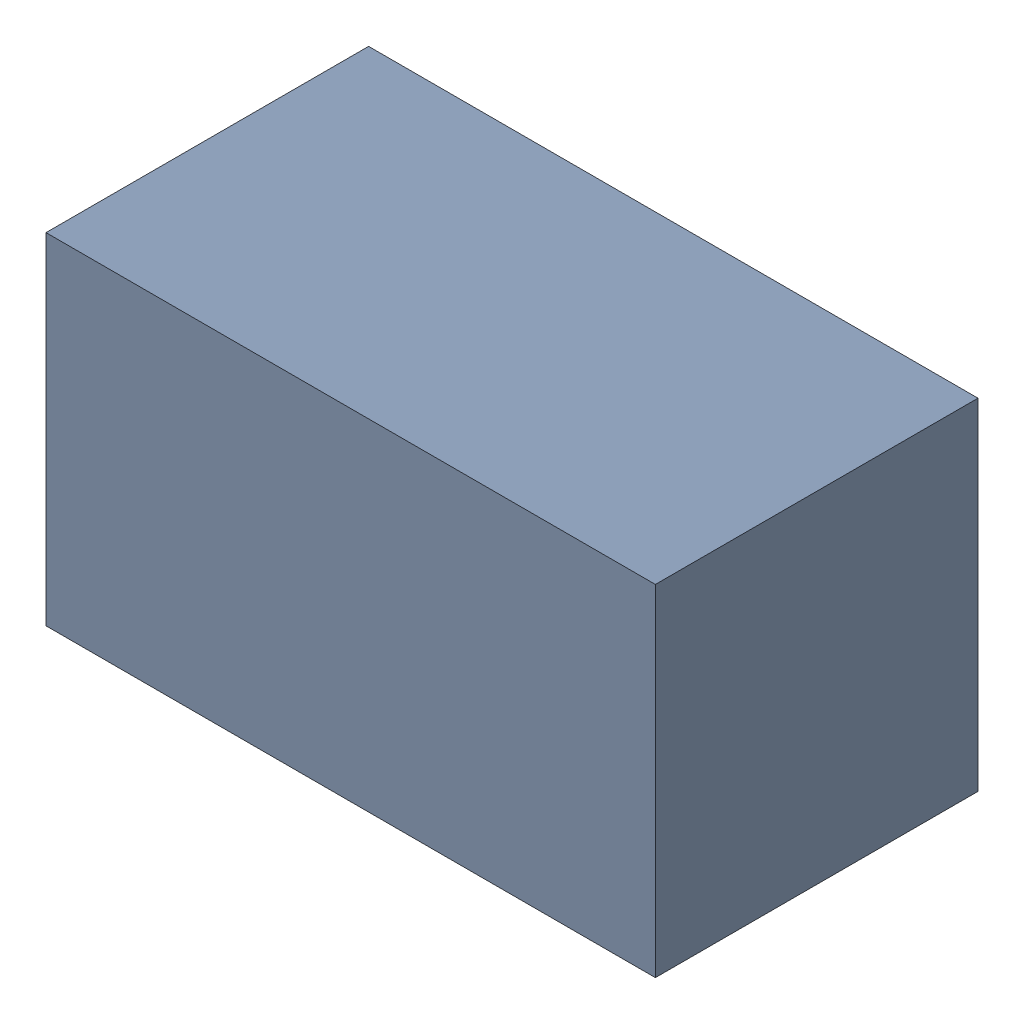
SolidWorks assembly R25, configuration Standard. Lengths in mm.
Overall size (1.7 0.95 0.9).
2 component instances, 1 part files, 0 mates.
Components (placement in the parent):
- 885541288-1: 885541288 [Standard] at (15.5 17.26 0) size (1.7 0.95 0.9)
  - Extruded_10-1: Extruded_10 [Standard] at origin size (1.7 0.95 0.9)
